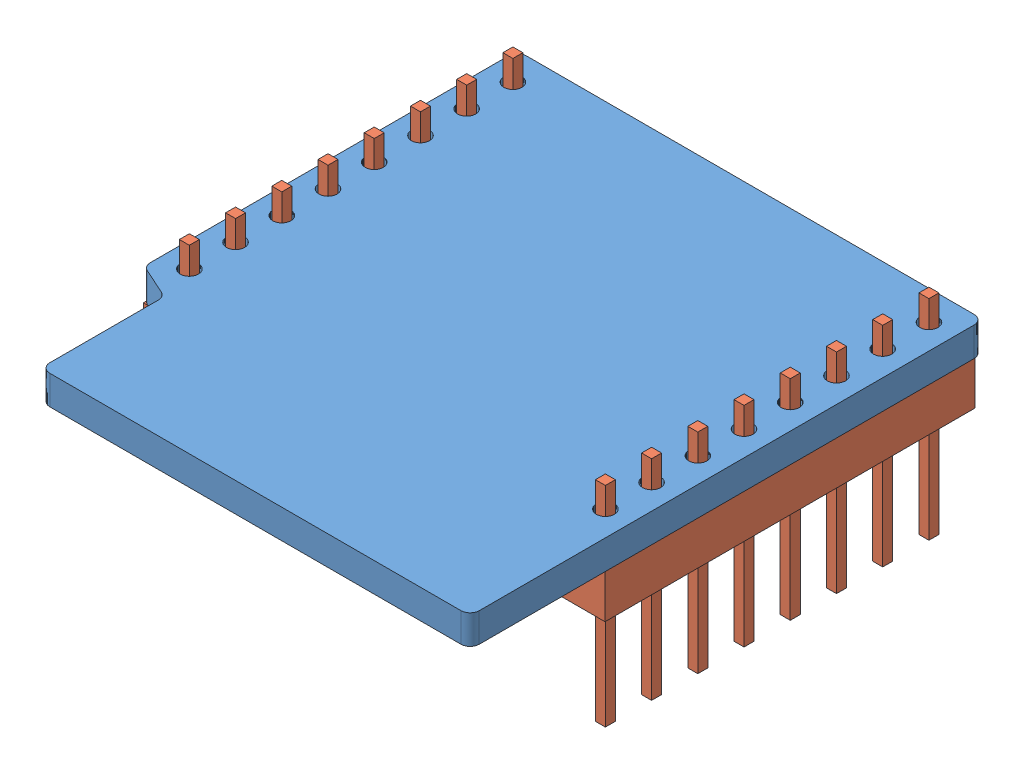
SolidWorks assembly LOLIN template, configuration Default. Lengths in mm.
Overall size (25.6 11.5 28.2).
3 component instances, 2 part files, 6 mates.
Components (placement in the parent):
- LOLIN template-1: LOLIN template [Default] at origin size (25.6 1.6 28.2)
- header_m8-1: header_m8 [Default] at (-11.43 -2.5 -27.85) x (0 0 1) z (-1 0 0) size (20.32 11.5 2.5)
- header_m8-2: header_m8 [Default] at (11.43 -2.5 -27.85) x (0 0 1) z (-1 0 0) size (20.32 11.5 2.5)
Mates (geometry in assembly coordinates):
- Coincident2: coincident anti-aligned: plane of breakout_template-1 through (0 0 0) normal (0 -1 0); plane of header_m8-1 through (-12.68 0 -27.85) normal (0 1 0)
- Coincident3: coincident anti-aligned: plane of breakout_template-1 through (0 0 0) normal (0 -1 0); plane of header_m8-2 through (10.18 0 -27.85) normal (0 1 0)
- Parallel1: parallel anti-aligned: plane of header_m8-1 through (-11.43 -2.5 -27.85) normal (-1 0 0)
- Parallel2: parallel anti-aligned: plane of header_m8-2 through (11.43 -2.5 -27.85) normal (-1 0 0)
- Coincident5: coincident aligned: line of breakout_template-1 through (-11.43 1.6 -26.58) axis (0 -1 0); line of header_m8-1 through (-11.43 -2.5 -26.58) axis (0 -1 0)
- Coincident6: coincident aligned: line of breakout_template-1 through (11.43 1.6 -26.58) axis (0 -1 0); line of header_m8-2 through (11.43 -2.5 -26.58) axis (0 -1 0)
